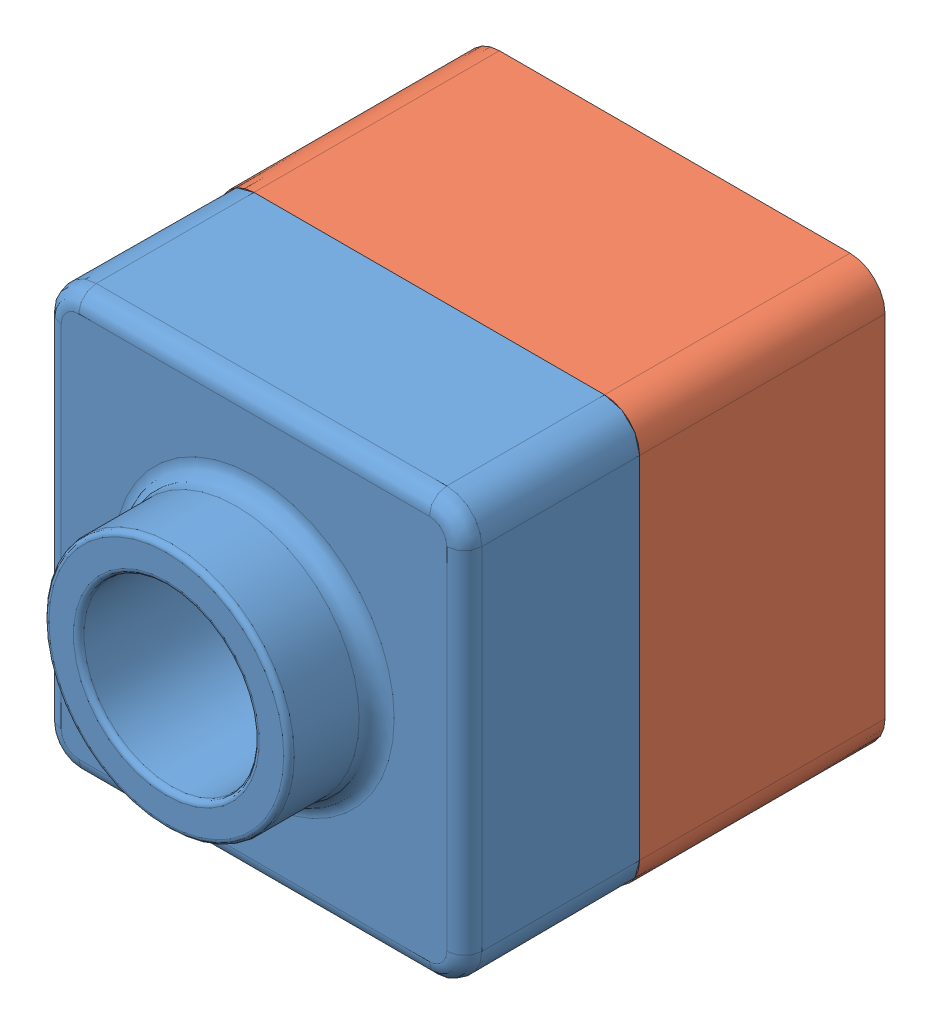
SolidWorks assembly solidworks_assembly, configuration Default. Lengths in mm.
Overall size (120 120 145).
2 component instances, 2 part files, 3 mates.
Components (placement in the parent):
- piece1-1: piece1 [Default] at (0.2713 -1.7477 46.5497) x (1 0 0) z (0 -1 0) size (120 75 120)
- Part2assemblies-1: Part2assemblies [Default] at (0.2713 -1.7477 -23.4503) size (120 120 90)
Mates (geometry in assembly coordinates):
- Coincident1: coincident: line of piece1-1 through (110.2713 118.2523 46.5497) axis (-1 0 0); line of Part2assemblies-1 through (241.7959 118.2523 46.5497) axis (-1 0 0)
- Coincident2: coincident: line of piece1-1 through (110.2713 118.2523 46.5497) axis (-1 0 0); line of Part2assemblies-1 through (241.7959 118.2523 46.5497) axis (-1 0 0)
- Coincident4: coincident anti-aligned: plane of piece1-1 through (2.2713 -1.7477 96.5497) normal (1 0 0); plane of Part2assemblies-1 through (2.2713 108.2523 46.5497) normal (-1 0 0)
